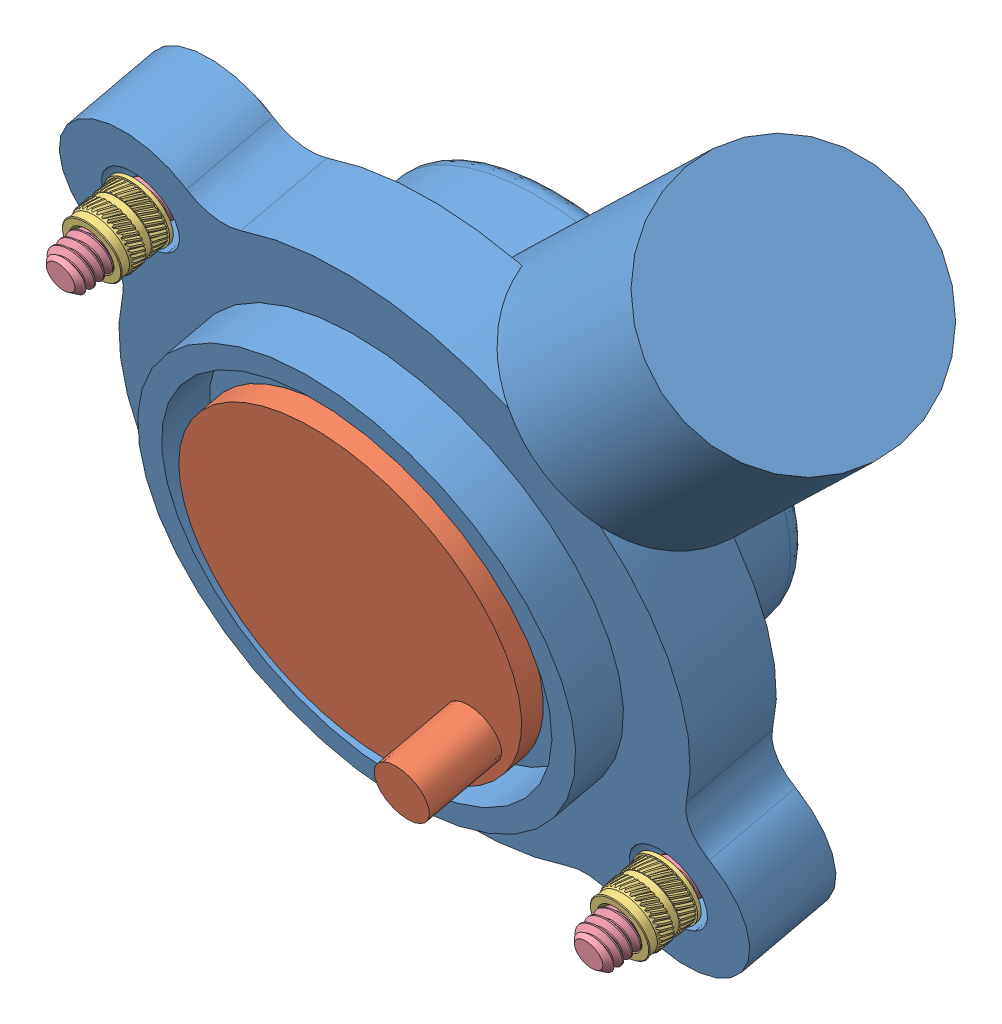
SolidWorks assembly ResistanceMonitoringAssembly, configuration Default. Lengths in mm.
Overall size (75.2 77.67 35.97).
8 component instances, 6 part files, 20 mates.
Components (placement in the parent):
- TPS_Adapter-1: TPS_Adapter [Default] at (0 -6.1784 30.4165) x (0 0 -1) z (1 0 0) size (36.6 16.94 25.4) (hidden)
- TPS-1: TPS [Default] at (0 1.6748 -7.2544) x (-0.707107 0.688984 0.159064) z (0.707107 0.688984 0.159064) size (52.5 19.56 53.85)
- TPS_Flywheel-1: TPS_Flywheel [Default] at (0 -0.5421 2.3482) x (0.251706 -0.942999 -0.217708) z (0 -0.224951 0.97437) size (22.86 22.86 19.56)
- TPS_Mount-1: TPS_Mount [Default] at (0 -61.1343 -14.114) x (-1 0 0) z (0 0.224951 -0.97437) size (138.43 82.55 3.44) (hidden)
- 93365A120_HEAT-SET INSERTS FOR PLASTICS (1)-1: 93365A120_HEAT-SET INSERTS FOR PLASTICS (1) [93365A120] at (14.7276 -14.0352 -4.6771) x (1 0 0) z (0 0.97437 0.224951) size (4.37 3.82 4.37)
- 93365A120_HEAT-SET INSERTS FOR PLASTICS (1)-2: 93365A120_HEAT-SET INSERTS FOR PLASTICS (1) [93365A120] at (-14.7276 14.6651 1.9489) x (1 0 0) z (0 0.97437 0.224951) size (4.37 3.82 4.37)
- 92210A110_18-8 STAINLESS STEEL HEX DRIVE FLAT HEAD SCREW-1: 92210A110_18-8 STAINLESS STEEL HEX DRIVE FLAT HEAD SCREW [92210A110] at (14.7276 -12.4382 -11.5947) x (-0.872461 -0.476159 -0.10993) z (0 0.224951 -0.97437) size (6.48 6.48 13.02)
- 92210A110_18-8 STAINLESS STEEL HEX DRIVE FLAT HEAD SCREW-2: 92210A110_18-8 STAINLESS STEEL HEX DRIVE FLAT HEAD SCREW [92210A110] at (-14.7276 16.2621 -4.9687) x (-0.872461 -0.476159 -0.10993) z (0 0.224951 -0.97437) size (6.48 6.48 13.02)
Mates (geometry in assembly coordinates):
- Coincident12: coincident anti-aligned: plane of TPS_Mount-1 through (66.5313 -4.3606 -1.0067) normal (0 -0.224951 0.97437)
- Coincident14: coincident anti-aligned: plane of TPS_Mount-1 through (0 -61.1343 -14.114) normal (-1 0 0)
- Concentric14: concentric: cylinder of TPS_Mount-1 through (0 0.3149 -1.3641) axis (0 -0.224951 0.97437) radius 15.4305
- Coincident20: coincident: axis of TPS_Adapter-1 through (0 -12.122 15.24) axis (0 1 0)
- Coincident21: coincident aligned: plane of TPS_Adapter-1 through (0 -6.1784 30.4165) normal (1 0 0)
- Concentric15: concentric aligned: cylinder of TPS-1 through (0 2.7147 -11.7587) axis (0 -0.224951 0.97437) radius 4.8895; cylinder of TPS_Flywheel-1 through (0 2.7147 -11.7587) axis (0 -0.224951 0.97437) radius 4.7625
- Concentric16: concentric aligned: cylinder of TPS-1 through (0 0.3149 -1.3641) axis (0 -0.224951 0.97437) radius 14.605; cylinder of TPS_Mount-1 through (0 0.3149 -1.3641) axis (0 -0.224951 0.97437) radius 15.4305
- Coincident23: coincident anti-aligned: plane of TPS-1 through (0 0.3149 -1.3641) normal (0 -0.224951 0.97437); plane of TPS_Mount-1 through (66.5313 -4.0457 -2.3708) normal (0 0.224951 -0.97437)
- Concentric18: concentric anti-aligned: cylinder of TPS-1 through (-14.7276 13.9109 5.2157) axis (0 0.224951 -0.97437) radius 2.6035; cylinder of TPS_Mount-1 through (-14.7276 14.6651 1.9489) axis (0 -0.224951 0.97437) radius 2.0193
- Slot3: slot aligned: cylinder of TPS_Flywheel-1 through (7.3066 -6.7484 6.129) axis (0 0.224951 -0.97437) radius 1.8415; plane of TPS_Adapter-1 through (9.7282 -5.227 8.5721) normal (0 -0.97437 -0.224951); cylinder of TPS_Adapter-1 through (9.7282 -7.2069 8.115) axis (0 0.224951 -0.97437) radius 2.032
- LimitDistance1: limit distance = -6.1784 mm: plane of assembly through (0 0 0) normal (0 1 0); plane of TPS_Adapter-1 through (0 -6.1784 30.4165) normal (0 1 0); plane of assembly
- Concentric19: concentric anti-aligned: cylinder of TPS_Mount-1 through (14.7276 -14.0352 -4.6771) axis (0 -0.224951 0.97437) radius 2.0193; cylinder of 93365A120_HEAT-SET INSERTS FOR PLASTICS (1)-1 through (14.7276 -14.0352 -4.6771) axis (0 0.224951 -0.97437) radius 1.9431
- Coincident26: coincident aligned: plane of TPS_Mount-1 through (66.5313 -4.817 0.9703) normal (0 -0.224951 0.97437); plane of 93365A120_HEAT-SET INSERTS FOR PLASTICS (1)-1 through (14.7276 -14.8066 -1.336) normal (0 -0.224951 0.97437)
- Concentric20: concentric anti-aligned: cylinder of TPS_Mount-1 through (-14.7276 14.6651 1.9489) axis (0 -0.224951 0.97437) radius 2.0193; cylinder of 93365A120_HEAT-SET INSERTS FOR PLASTICS (1)-2 through (-14.7276 14.6651 1.9489) axis (0 0.224951 -0.97437) radius 1.9431
- Coincident27: coincident aligned: plane of TPS_Mount-1 through (66.5313 -4.817 0.9703) normal (0 -0.224951 0.97437); plane of 93365A120_HEAT-SET INSERTS FOR PLASTICS (1)-2 through (-14.7276 13.8937 5.29) normal (0 -0.224951 0.97437)
- Concentric21: concentric anti-aligned: cylinder of TPS-1 through (14.7276 -14.7894 -1.4102) axis (0 0.224951 -0.97437) radius 2.6035; circle of 92210A110_18-8 STAINLESS STEEL HEX DRIVE FLAT HEAD SCREW-1
- Coincident28: coincident aligned: cone of TPS-1; cone of 92210A110_18-8 STAINLESS STEEL HEX DRIVE FLAT HEAD SCREW-1 through (14.7276 -12.9124 -9.5405) axis (0 -0.224951 0.97437)
- Concentric22: concentric anti-aligned: cylinder of TPS-1 through (-14.7276 13.9109 5.2157) axis (0 0.224951 -0.97437) radius 2.6035; line of 92210A110_18-8 STAINLESS STEEL HEX DRIVE FLAT HEAD SCREW-2 through (-14.7276 15.7879 -2.9145) axis (0 -0.224951 0.97437)
- Coincident29: coincident aligned: circle of TPS-1; cone of 92210A110_18-8 STAINLESS STEEL HEX DRIVE FLAT HEAD SCREW-2 through (-14.7276 15.7879 -2.9145) axis (0 -0.224951 0.97437)
- Coincident30: coincident anti-aligned: plane of TPS-1 through (0 2.7147 -11.7587) normal (0 -0.224951 0.97437); plane of TPS_Flywheel-1 through (0 2.7147 -11.7587) normal (0 0.224951 -0.97437)
